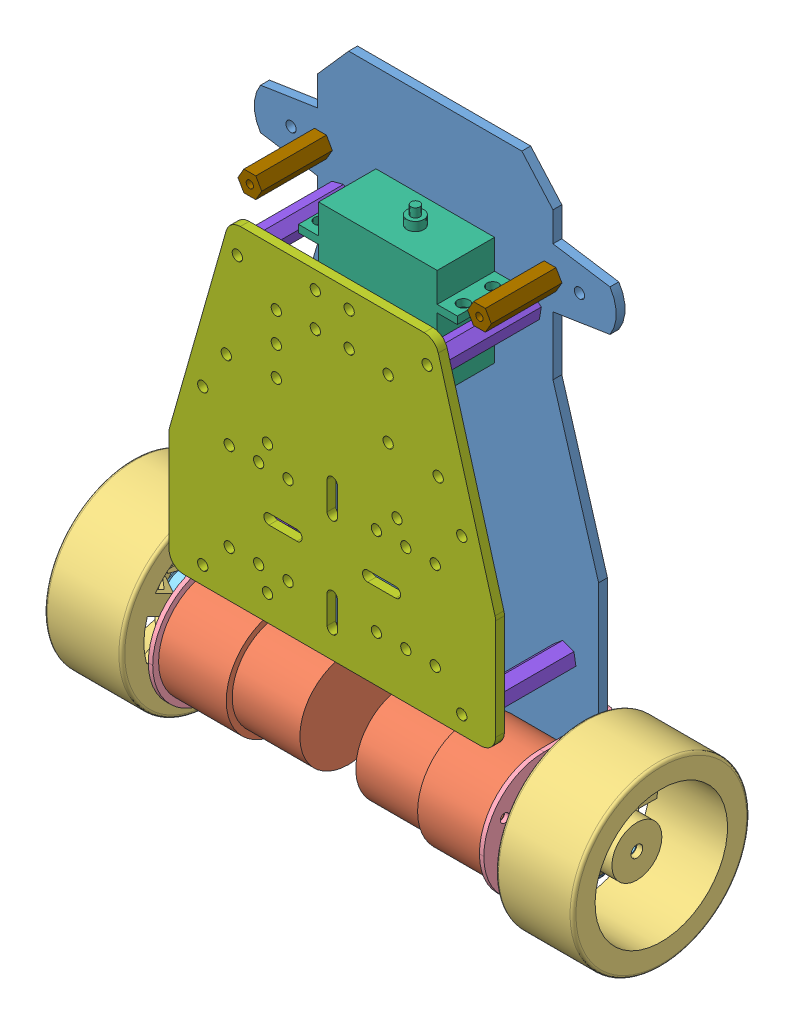
SolidWorks assembly 遥控车, configuration 默认. Lengths in mm.
Overall size (179.6 215.72 84.43).
17 component instances, 9 part files, 28 mates.
Components (placement in the parent):
- 下板-1: 下板 [默认] at (-29.0251 -56.0307 164.6441) size (123 204 3)
- AB-60电机-1: AB-60电机 [默认] at (-19.5251 -25.5307 187.6441) x (1 0 0) z (0 1 0) size (64 37 37)
- 车轮-1: 车轮 [默认] at (34.4749 -25.5307 180.6441) x (0 -0.773948 0.63325) z (1 0 0) size (60 60 26.3)
- 电机安装板-1: 电机安装板 [默认] at (-13.0251 -25.5307 163.1441) x (0 0 1) z (0 1 0) size (45 41 41)
- 电机联轴器-1: 电机联轴器 [默认] at (32.4749 -25.5307 180.6441) x (0 0.381849 -0.924225) z (0 -0.924225 -0.381849) size (14 18 12.3)
- 舵机MG995-1: 舵机MG995 [默认] at (-29.0251 80.9693 177.3941) x (1 0 0) z (0 1 0) size (54 19.5 43)
- 上板-1: 上板 [默认] at (-29.0251 40.9693 199.6441) size (111 112 3)
- 车轮-2: 车轮 [默认] at (-92.5251 -25.5307 180.6441) x (0 -0.773948 0.63325) z (-1 0 0) size (60 60 26.3)
- AB-60电机-2: AB-60电机 [默认] at (-38.5251 -25.5307 187.6441) x (-1 0 0) z (0 -1 0) size (64 37 37)
- 电机联轴器-2: 电机联轴器 [默认] at (-90.5251 -25.5307 180.6441) x (0 0.381849 -0.924225) z (0 0.924225 0.381849) size (14 18 12.3)
- 电机安装板-2: 电机安装板 [默认] at (-45.0251 -25.5307 163.1441) x (0 0 1) z (0 -1 0) size (45 41 41)
- 支撑柱子-1: 支撑柱子 [默认] at (-73.0251 6.9693 199.6441) x (-0.701839 0.712335 0) z (0 0 -1) size (8.08 7 38)
- 支撑柱子-2: 支撑柱子 [默认] at (3.2249 103.9693 199.6441) x (-0.773068 0.634323 0) z (0 0 -1) size (8.08 7 38)
- 支撑柱子-3: 支撑柱子 [默认] at (-61.2751 103.9693 199.6441) x (-0.701839 0.712335 0) z (0 0 -1) size (8.08 7 38)
- 支撑柱子-4: 支撑柱子 [默认] at (14.9749 6.9693 199.6441) x (-0.93819 0.34612 0) z (0 0 -1) size (8.08 7 38)
- 转柱-1: 转柱 [默认] at (9.9749 115.9693 167.6441) size (8.08 7 24)
- 转柱-2: 转柱 [默认] at (-68.0251 115.9693 167.6441) size (8.08 7 24)
Mates (geometry in assembly coordinates):
- 重合1: coincident: plane of AB-60电机-1 through (26.4749 -25.5307 187.6441) normal (1 0 0); plane of 电机安装板-1 through (26.4749 -5.0307 163.1441) normal (-1 0 0)
- 同心1: concentric: cylinder of AB-60电机-1 through (26.4749 -33.2807 201.0675) axis (1 0 0) radius 1.25; circle of 电机安装板-1
- 同心2: concentric: circle of AB-60电机-1; cylinder of 电机安装板-1 through (27.9749 -17.7807 201.0675) axis (1 0 0) radius 1.5
- 重合3: coincident: plane of 下板-1 through (-78.0251 115.9693 164.6441) normal (0 0 -1); plane of 电机安装板-1 through (-13.0251 -5.0307 164.6441) normal (0 0 1)
- 重合4: coincident: plane of 下板-1 through (26.4749 33.9693 167.6441) normal (1 0 0); plane of 电机安装板-1 through (26.4749 -5.0307 163.1441) normal (-1 0 0)
- 距离1: distance = 10 mm: plane of 电机安装板-1 through (25.7383 -46.0307 165.3807) normal (0 -1 0); plane of 下板-1 through (-84.5251 -56.0307 167.6441) normal (0 -1 0)
- 同心3: concentric: cylinder of AB-60电机-1 through (26.4749 -25.5307 180.6441) axis (-1 0 0) radius 3; cylinder of 电机联轴器-1 through (32.4749 -25.5307 180.6441) axis (-1 0 0) radius 5.5
- 重合6: coincident: plane of AB-60电机-1 through (32.4749 -25.5307 183.6441) normal (1 0 0); plane of 电机联轴器-1 through (32.4749 -23.4305 175.5609) normal (-1 0 0)
- 同心4: concentric: cylinder of 车轮-1 through (60.7749 -25.5307 180.6441) axis (-1 0 0) radius 22.5; cylinder of 电机联轴器-1 through (32.4749 -25.5307 180.6441) axis (-1 0 0) radius 5.5
- 重合7: coincident: plane of 车轮-1 through (50.4749 -25.5307 180.6441) normal (-1 0 0); plane of 电机联轴器-1 through (50.4749 -25.5307 180.6441) normal (1 0 0)
- 距离2: distance = 32 mm: plane of 下板-1 through (-78.0251 115.9693 167.6441) normal (0 0 1); plane of 上板-1 through (-29.0251 40.9693 199.6441) normal (0 0 -1)
- 宽度1: width: plane of 上板-1 through (-84.5251 40.9693 202.6441) normal (-1 0 0); plane of 上板-1 through (26.4749 0.9693 202.6441) normal (1 0 0); plane of 下板-1 through (-84.5251 33.9693 167.6441) normal (-1 0 0); plane of 下板-1 through (26.4749 33.9693 167.6441) normal (1 0 0)
- 距离3: distance = 63 mm: line of 上板-1 through (14.9749 6.9693 199.6441) axis (0 0 1); plane of 下板-1 through (-84.5251 -56.0307 167.6441) normal (0 -1 0)
- 重合10: coincident: plane of 下板-1 through (-78.0251 115.9693 167.6441) normal (0 0 1); plane of 舵机MG995-1 through (-49.1751 117.9693 167.6441) normal (0 0 -1)
- 宽度2: width: plane of 下板-1 through (-84.5251 33.9693 167.6441) normal (-1 0 0); plane of 下板-1 through (26.4749 33.9693 167.6441) normal (1 0 0); plane of 舵机MG995-1 through (-49.1751 117.9693 167.6441) normal (-1 0 0); plane of 舵机MG995-1 through (-8.8751 117.9693 167.6441) normal (1 0 0)
- 距离4: distance = 5 mm: plane of 舵机MG995-1 through (-29.0251 107.9693 177.3941) normal (0 1 0); plane of 上板-1 through (5.9749 112.9693 202.6441) normal (0 1 0)
- 同心5: concentric: cylinder of 下板-1 through (-73.0251 6.9693 164.6441) axis (0 0 -1) radius 2; cylinder of 支撑柱子-1 through (-73.0251 6.9693 161.6441) axis (0 0 1) radius 1.5
- 重合12: coincident: plane of 下板-1 through (-78.0251 115.9693 167.6441) normal (0 0 1); plane of 支撑柱子-1 through (-73.0251 6.9693 167.6441) normal (0 0 -1)
- 同心6: concentric: cylinder of 下板-1 through (-61.2751 103.9693 164.6441) axis (0 0 -1) radius 2; cylinder of 支撑柱子-3 through (-61.2751 103.9693 161.6441) axis (0 0 1) radius 1.5
- 同心7: concentric: cylinder of 下板-1 through (3.2249 103.9693 164.6441) axis (0 0 -1) radius 2; cylinder of 支撑柱子-2 through (3.2249 103.9693 161.6441) axis (0 0 1) radius 1.5
- 同心8: concentric: cylinder of 下板-1 through (14.9749 6.9693 164.6441) axis (0 0 -1) radius 2; cylinder of 支撑柱子-4 through (14.9749 6.9693 161.6441) axis (0 0 1) radius 1.5
- 重合13: coincident: plane of 下板-1 through (-78.0251 115.9693 167.6441) normal (0 0 1); plane of 支撑柱子-4 through (14.9749 6.9693 167.6441) normal (0 0 -1)
- 重合14: coincident: plane of 上板-1 through (-29.0251 40.9693 199.6441) normal (0 0 -1); plane of 支撑柱子-3 through (-61.2751 103.9693 199.6441) normal (0 0 1)
- 重合15: coincident: plane of 上板-1 through (-29.0251 40.9693 199.6441) normal (0 0 -1); plane of 支撑柱子-2 through (3.2249 103.9693 199.6441) normal (0 0 1)
- 同心9: concentric: cylinder of 下板-1 through (9.9749 115.9693 167.6441) axis (0 0 -1) radius 1.75; cylinder of 转柱-1 through (9.9749 115.9693 191.6441) axis (0 0 1) radius 1.25
- 重合16: coincident: plane of 下板-1 through (-78.0251 115.9693 167.6441) normal (0 0 1); plane of 转柱-1 through (9.9749 115.9693 167.6441) normal (0 0 -1)
- 同心10: concentric: cylinder of 下板-1 through (-68.0251 115.9693 167.6441) axis (0 0 -1) radius 1.75; circle of 转柱-2
- 重合17: coincident: plane of 下板-1 through (-78.0251 115.9693 167.6441) normal (0 0 1); plane of 转柱-2 through (-68.0251 115.9693 167.6441) normal (0 0 -1)
